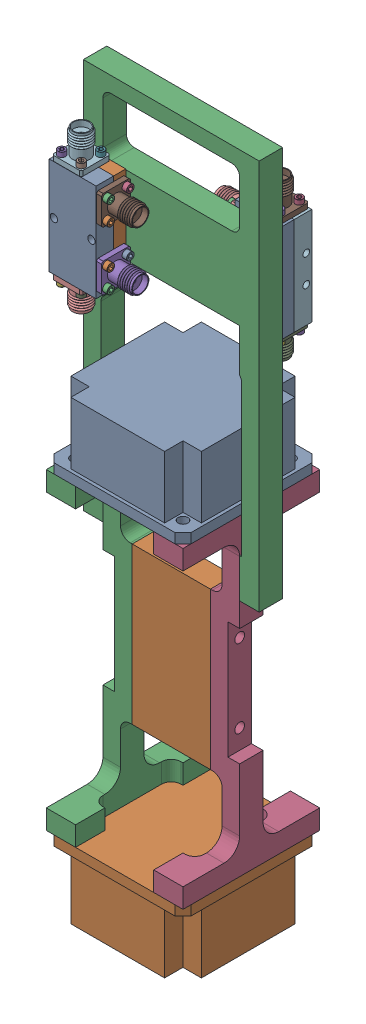
SolidWorks assembly Assem2, configuration Default. Lengths in mm.
Overall size (58.59 227.96 44.45).
8 component instances, 5 part files, 19 mates.
Components (placement in the parent):
- switch-1: switch [Default] at (-1.6529 3.056 -1.204) size (44.45 23.32 44.45)
- switch-2: switch [Default] at (-1.6529 -98.544 -1.204) x (0 0 -1) z (-1 0 0) size (44.45 23.32 44.45)
- i-bracket-1: i-bracket [Default] at (-23.8779 -47.744 -1.204) x (0 -1 0) z (0 0 1) size (101.6 9.53 44.45)
- i-bracket-2: i-bracket [Default] at (20.5721 -47.744 -1.204) x (0 1 0) z (0 0 1) size (101.6 9.53 44.45)
- Coupler-1: Coupler [Default] at (-24.0528 66.3302 6.543) x (0 1 0) z (0 0 -1) size (50.8 24.77 9.65)
- pi-bracket-1: pi-bracket [Default] at (-1.6529 42.5962 -5.014) size (57.15 127 7.62)
- Coupler-2: Coupler [Default] at (19.121 67.8837 -8.951) x (0 1 0) z (0 0 1) size (50.8 24.77 9.65)
- center-plate-1: center-plate [Default] at (-1.6529 -47.744 -5.014) size (25.4 50.8 7.62)
Mates (geometry in assembly coordinates):
- Concentric1: concentric anti-aligned: cylinder of switch-1 through (15.8096 3.056 16.2585) axis (0 1 0) radius 1.5875; cylinder of switch-2 through (15.8096 -98.544 16.2585) axis (0 -1 0) radius 1.5875
- Concentric2: concentric anti-aligned: cylinder of switch-1 through (15.8096 3.056 -18.6665) axis (0 1 0) radius 1.5875; cylinder of switch-2 through (15.8096 -98.544 -18.6665) axis (0 -1 0) radius 1.5875
- Coincident1: coincident aligned: plane of switch-1 through (-23.8779 6.231 21.021) normal (-1 0 0); plane of i-bracket-1 through (-23.8779 -47.744 -1.204) normal (-1 0 0)
- Coincident2: coincident anti-aligned: plane of switch-1 through (-1.6529 3.056 -1.204) normal (0 -1 0); plane of i-bracket-1 through (-14.3529 3.056 21.021) normal (0 1 0)
- Coincident3: coincident aligned: plane of switch-2 through (-23.8779 -101.719 21.021) normal (-1 0 0); plane of i-bracket-1 through (-23.8779 -47.744 -1.204) normal (-1 0 0)
- Coincident4: coincident anti-aligned: plane of switch-2 through (-1.6529 -98.544 -1.204) normal (0 1 0); plane of i-bracket-1 through (-14.3529 -98.544 21.021) normal (0 -1 0)
- Coincident5: coincident aligned: plane of switch-1 through (20.5721 6.231 21.021) normal (1 0 0); plane of i-bracket-2 through (19.3935 -48.9347 -1.2693) normal (1 0 0)
- Coincident6: coincident anti-aligned: plane of switch-1 through (-1.6529 3.056 -1.204) normal (0 -1 0); plane of i-bracket-2 through (9.8685 1.8653 20.9557) normal (0 1 0)
- Coincident7: coincident anti-aligned: plane of i-bracket-2 through (19.3935 -48.9347 -1.2693) normal (1 0 0); plane of pi-bracket-1 through (20.5721 101.0162 -5.1005) normal (-1 0 0)
- Coincident8: coincident aligned: plane of i-bracket-2 through (19.3935 -93.3847 2.5407) normal (0 0 1); plane of pi-bracket-1 through (-1.6529 42.5962 2.5195) normal (0 0 1)
- Coincident9: coincident anti-aligned: plane of Coupler-1 through (-24.0528 66.3302 2.5195) normal (0 0 -1); plane of pi-bracket-1 through (-1.6529 42.5962 2.5195) normal (0 0 1)
- Parallel1: parallel aligned: plane of Coupler-1 through (-24.0528 82.2052 6.4565) normal (0 1 0); plane of pi-bracket-1 through (-30.2279 106.0962 2.5195) normal (0 1 0)
- Coincident11: coincident anti-aligned: plane of pi-bracket-1 through (-1.6529 42.5962 -5.1005) normal (0 0 -1); plane of Coupler-2 through (19.121 67.8837 -5.1005) normal (0 0 1)
- Parallel2: parallel aligned: plane of pi-bracket-1 through (-30.2279 106.0962 2.5195) normal (0 1 0); plane of Coupler-2 through (19.121 83.7587 -9.0375) normal (0 1 0)
- Coincident13: coincident anti-aligned: plane of i-bracket-1 through (-14.3529 -47.744 -1.204) normal (1 0 0); plane of center-plate-1 through (-14.3529 -73.144 2.606) normal (-1 0 0)
- Coincident14: coincident aligned: plane of i-bracket-1 through (-23.8779 -3.294 -5.014) normal (0 0 -1); plane of center-plate-1 through (-1.6529 -47.744 -5.014) normal (0 0 -1)
- Coincident15: coincident aligned: line of i-bracket-1 through (-14.3529 -22.344 2.606) axis (0 0 -1); line of center-plate-1 through (-14.3529 -22.344 2.606) axis (0 0 -1)
- Coincident16: coincident aligned: plane of switch-2 through (-23.8779 -101.719 -23.429) normal (0 0 -1); plane of i-bracket-1 through (-14.3529 3.056 -23.429) normal (0 0 -1)
- Coincident17: coincident aligned: plane of switch-2 through (-23.8779 -101.719 -23.429) normal (0 0 -1); plane of i-bracket-2 through (11.0471 -98.544 -23.429) normal (0 0 -1)
